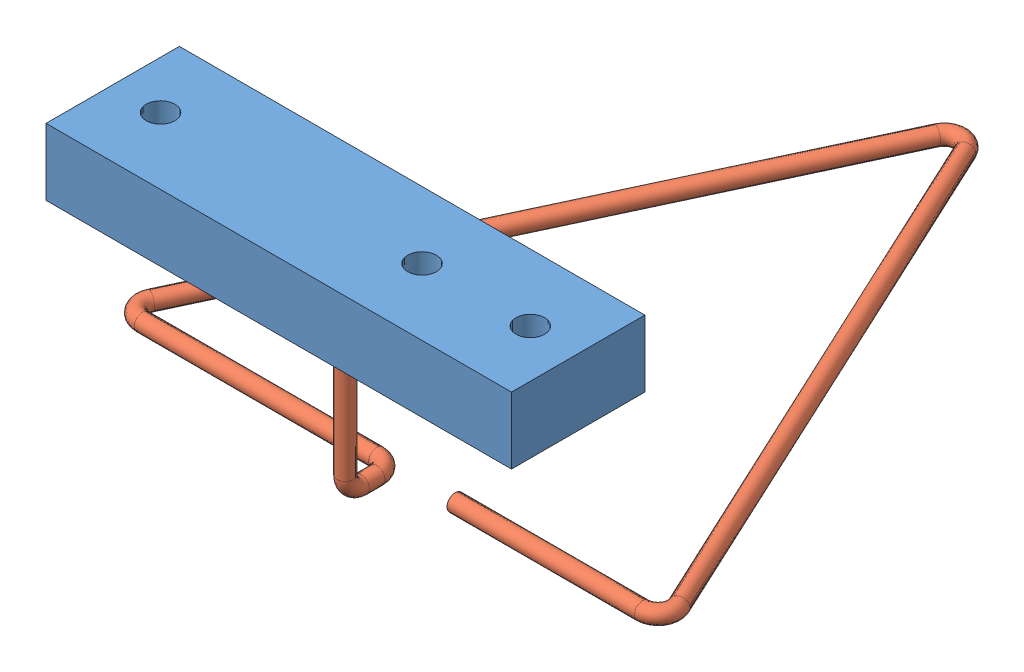
SolidWorks assembly Montagem_Triangulo, configuration Valor predeterminado. Lengths in mm.
Overall size (104.75 46.93 131.82).
2 component instances, 2 part files, 0 mates.
Components (placement in the parent):
- Suporte Arames-1: Suporte Arames [Valor predeterminado] at (41.7157 -6.8855 101.75) size (89 12.75 25.5)
- Triangulo-1: Triangulo [Valor predeterminado] at (-2.7843 -39.4855 84.5) size (104.75 34.19 120.66)
